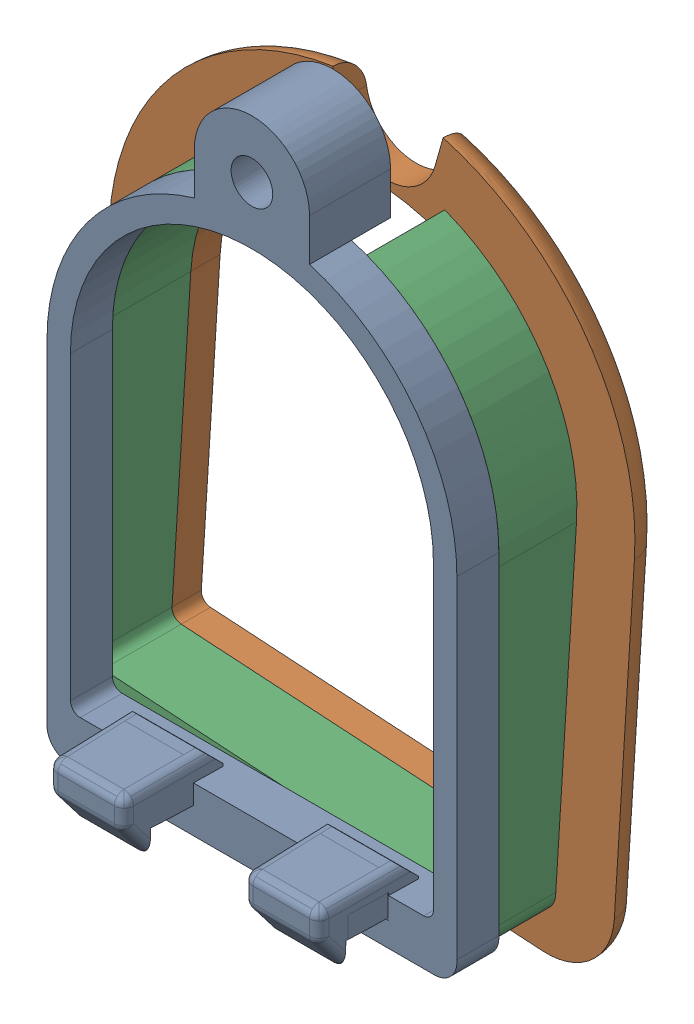
SolidWorks assembly 装配体11, configuration 默认. Lengths in mm.
Overall size (28.97 35.98 11.25).
3 component instances, 3 part files, 5 mates.
Components (placement in the parent):
- 实体1-1: 实体1 [默认] at (-5.8953 4.7868 -8.3251) size (21.01 33.45 7.66)
- 实体2-1: 实体2 [默认] at (-5.8953 4.7868 -8.3251) x (0.998051 -0.062404 0) z (0 0 1) size (26.95 33.23 1.67)
- 实体3-1: 实体3 [默认] at (-5.8953 4.7868 -8.3251) x (0.998051 -0.062404 0) z (0 0 1) size (21.01 28.27 4)
Mates (geometry in assembly coordinates):
- 重合1: coincident anti-aligned: plane of 实体1-1 through (-5.8953 4.7868 -2.8251) normal (0 0 -1); plane of 实体3-1 through (-5.8953 4.7868 -2.8251) normal (0 0 1)
- 同心1: concentric aligned: cylinder of 实体1-1 through (-5.8953 4.7868 -0.6751) axis (0 0 -1) radius 10.5; cylinder of 实体3-1 through (-5.8953 4.7868 -0.6751) axis (0 0 -1) radius 10.5
- 同心2: concentric aligned: cylinder of 实体2-1 through (-5.8953 4.7868 48.5219) axis (0 0 -1) radius 9.3; cylinder of 实体3-1 through (-5.8953 4.7868 48.5219) axis (0 0 -1) radius 9.3
- 重合3: coincident anti-aligned: plane of 实体2-1 through (-7.4866 1.7011 -6.8251) normal (0 0 1); plane of 实体3-1 through (2.3699 -12.8556 -6.8251) normal (0 0 -1)
- 重合4: coincident aligned: line of 实体2-1 through (-14.1608 9.0495 -6.8251) axis (-0.458352 -0.888771 0); line of 实体3-1 through (-15.1772 5.3672 -6.8251) axis (-0.062404 -0.998051 0)
